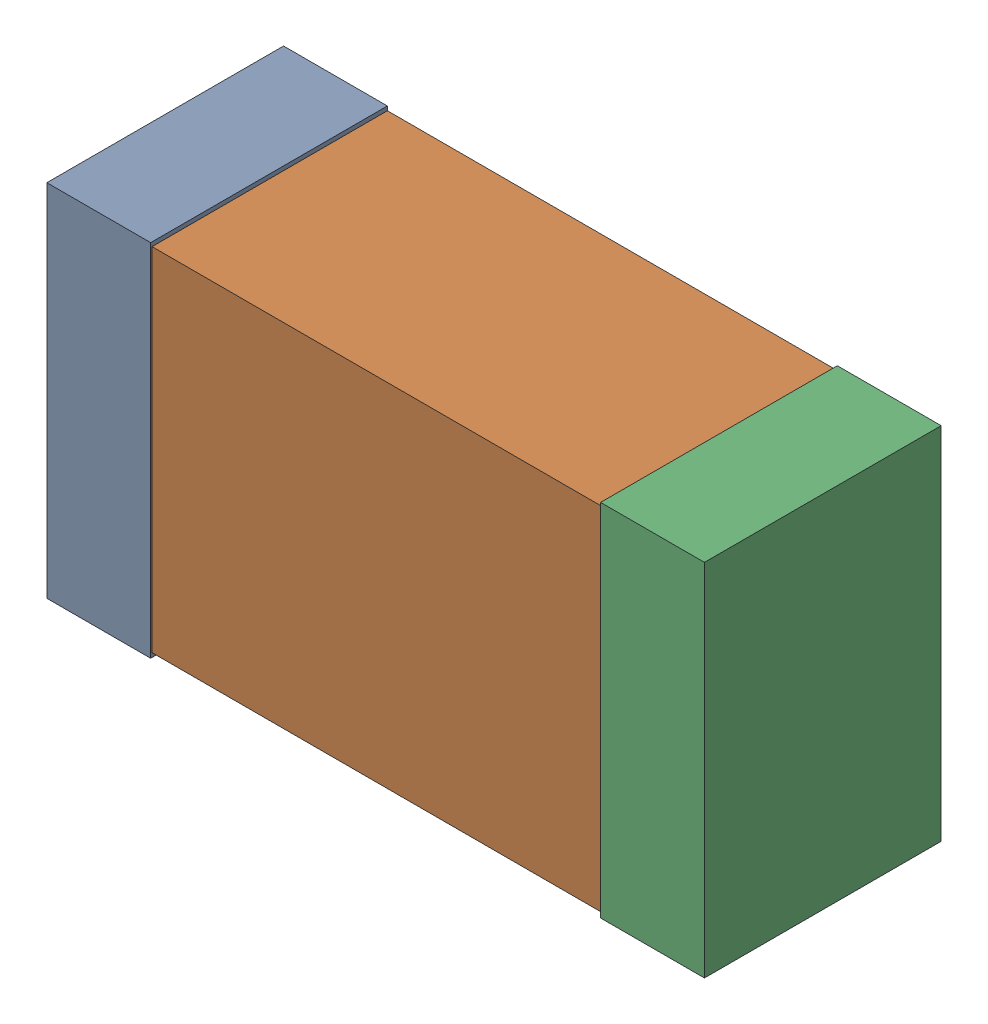
SolidWorks assembly C5Kanaloa_v2.0.0_GPIO_b, configuration Default. Lengths in mm.
Overall size (2.38 1.3 0.85).
6 component instances, 2 part files, 0 mates.
Components (placement in the parent):
- 352877648-1: 352877648 [Default] at (82.185 47.625 0) size (0.38 1.3 0.85)
  - Extruded_14-1: Extruded_14 [Default] at origin size (0.38 1.3 0.85)
- 352877392-1: 352877392 [Default] at (83.185 47.625 0) size (2.2 1.27 0.85)
  - Extruded_15-1: Extruded_15 [Default] at origin size (2.2 1.27 0.85)
- 352877648-2: 352877648 [Default] at (84.185 47.625 0) size (0.38 1.3 0.85)
  - Extruded_14-1: Extruded_14 [Default] at origin size (0.38 1.3 0.85)
